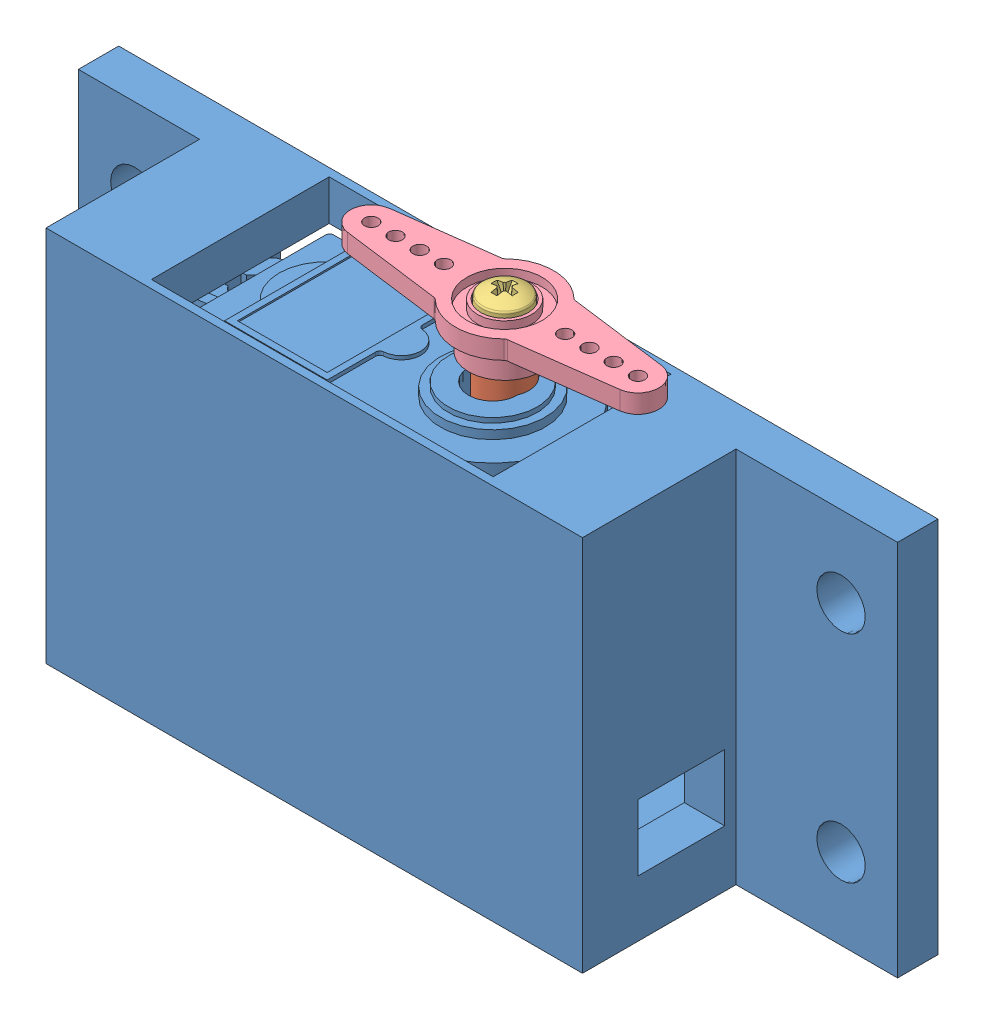
SolidWorks assembly Assemblage1, configuration Défaut. Lengths in mm.
Overall size (101.4 55.54 24).
9 component instances, 8 part files, 0 mates.
Components (placement in the parent):
- FS5109M_corps-1: FS5109M_corps [Défaut] at (-14.4616 14.2221 101.4) size (101.4 46.7 24)
- FS5109M_Ensemble arbre-1: FS5109M_Ensemble arbre [2S] at (-4.1421 -10.9414 100.1617) size (38.2 14.35 12.15)
  - FS5109M_arbre-1: FS5109M_arbre [Défaut] at origin size (6 10 6)
  - pan head cross recess screw_iso-1: pan head cross recess screw_iso [ISO 7045 - M3 x 12 - Z --- 12N] at (0 47.65 0) x (0 -1 0) z (0 0 1) size (14.35 5.6 5.6)
  - FS5109M_palo 2S-1: FS5109M_palo 2S [Défaut] at (0 44.2 0) size (38.2 5.6 12.15)
  - FS5109M_palo 2B-1: FS5109M_palo 2B [Défaut] at (0 44.2 0) size (55.74 7.8 13.34) (hidden)
  - FS5109M_palo C-1: FS5109M_palo C [Défaut] at (0 44.2 0) size (20.9 5.6 20.9) (hidden)
  - FS5109M_palo 4-1: FS5109M_palo 4 [Défaut] at (0 44.2 0) size (36.6 5.6 36.6) (hidden)
  - FS5109M_palo 6-1: FS5109M_palo 6 [Défaut] at (0 44.2 0) size (31.74 5.6 28.12) (hidden)
